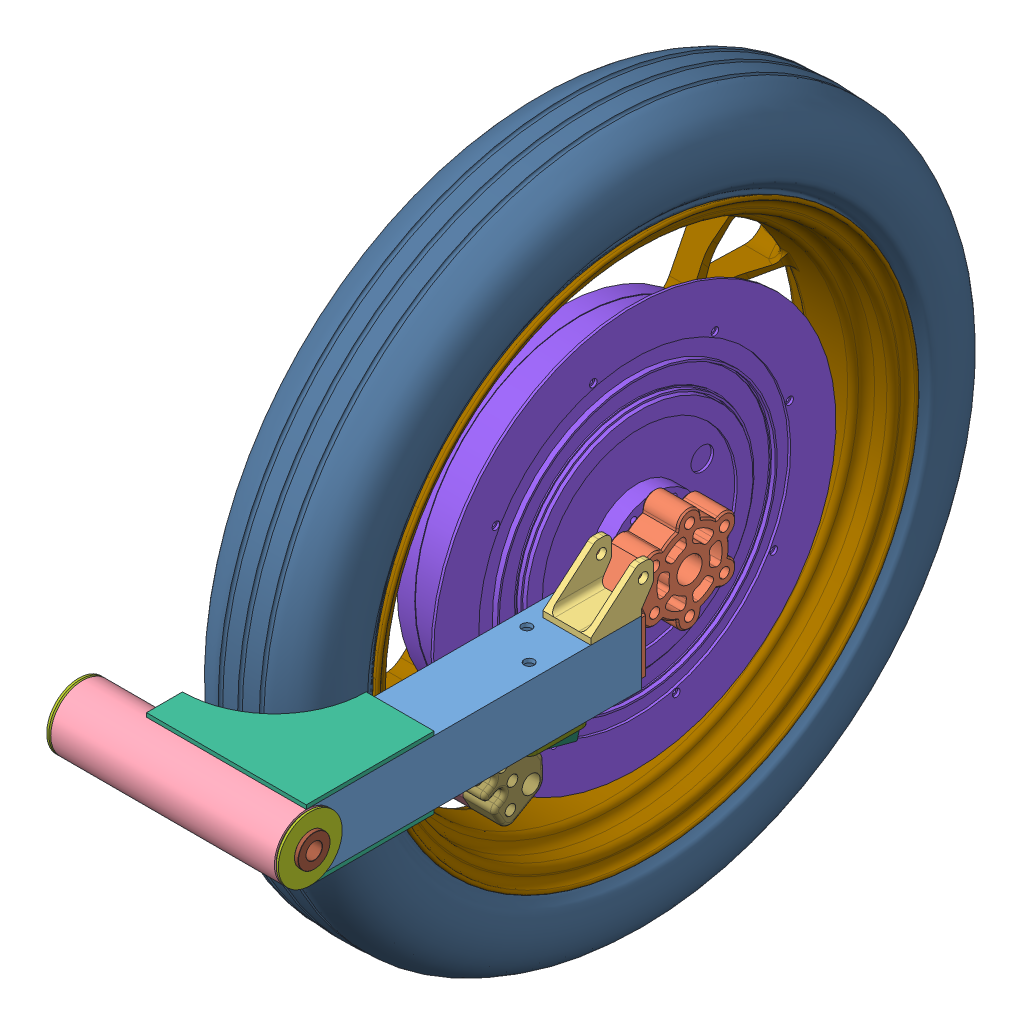
SolidWorks assembly Rear Round Tube Assembly, configuration Default. Lengths in mm.
Overall size (190.5 437.13 595.81).
21 component instances, 16 part files, 42 mates.
Components (placement in the parent):
- Rear Torque Tube-1: Rear Torque Tube [Default] at (-90.1765 35.8174 163.51) size (50.8 50.8 260.35)
- Rear Cap insert-1: Rear Cap insert [Default] at (-42.5515 83.4424 163.51) x (-1 0 0) z (0 0 1) size (63.5 83.05 151.54)
- Rear Brake Bracket-1: Rear Brake Bracket [Default] at (-58.4265 91.3799 178.985) x (1 0 0) z (0 0 -1) size (38.1 36.51 50)
- Rear Round Tube-1: Rear Round Tube [Default] at (-217.1515 61.2174 430.21) x (1 0 0) z (0 -0.469163 -0.883112) size (177.8 50.8 50.8)
- Half Moon Bracket-1: Half Moon Bracket [Default] at (-166.3765 61.2174 430.21) x (0 0 -1) z (0 -1 0) size (22.4 3.17 50.8)
- Rear Gusset-1: Rear Gusset [Default] at (-67.947 35.8174 204.98) x (-1 0 0) z (0 -1 0) size (127 101.6 3.17)
- Rear Gusset-2: Rear Gusset [Default] at (-67.947 89.7924 204.98) x (-1 0 0) z (0 -1 0) size (127 101.6 3.17)
- Rear End Cap-1: Rear End Cap [Default] at (-220.3265 61.2174 430.21) x (1 0 0) z (0 0.040114 0.999195) size (15.88 50.8 50.8)
- Rear End Cap-2: Rear End Cap [Default] at (-36.1765 61.2174 430.21) x (-1 0 0) z (0 -0.104999 -0.994472) size (15.88 50.8 50.8)
- Motor Mitsuba M2096 D-III-1: Motor Mitsuba M2096 D-III [Default] at (-165.0515 61.2174 87.31) x (0 0.866025 -0.5) z (0 0.5 0.866025) size (320 108 320)
- rimmachined v13.2-1: rimmachined v13.2 [Default] at (-156.7515 61.2174 87.31) x (-1 0 0) z (0 0.911723 -0.410807) size (93.59 431.57 431.57) (hidden)
- Michelin Tire-1: Michelin Tire [Default] at (-156.7515 61.2174 87.31) x (-1 0 0) z (0 0 1) size (101.13 556.61 556.61) (hidden)
- 6338K423_Oil-Embedded Flanged Sleeve Bearing (1)-1: 6338K423_Oil-Embedded Flanged Sleeve Bearing (1) [6338K423] at (-213.9765 61.2174 430.21) x (0 0 1) z (-1 0 0) size (25.4 25.4 19.05)
- 6338K423_Oil-Embedded Flanged Sleeve Bearing (1)-3: 6338K423_Oil-Embedded Flanged Sleeve Bearing (1) [6338K423] at (-42.5265 61.2174 430.21) x (0 -0.063789 -0.997963) z (1 0 0) size (25.4 25.4 19.05)
- Caliper Assembly.iam-2: Caliper Assembly.iam [Default] at (-112.6015 -15.8951 220.8728) x (0 0.866025 0.5) z (1 0 0) size (113.01 113.01 50.55)
  - Caliper A v2.ipt-1: Caliper A v2.ipt [Default] x (-1 0 0) z (0 0 -1) size (69.85 44.45 25.27)
  - Caliper B v9.ipt-1: Caliper B v9.ipt [Default] at origin size (69.85 44.45 25.27)
  - MCP 554 Pads v5.ipt-1: MCP 554 Pads v5.ipt [Default] at (0.0125 -5.95 -15.4307) x (-1 0 0) z (0 0 -1) size (63.75 26 7.7)
  - MCP 554 Pads v5.ipt-2: MCP 554 Pads v5.ipt [Default] at (-0.0125 -5.95 -3.5) size (63.75 26 7.7)
  - MCP FWB caliper mounting bracket v1.ipt-1: MCP FWB caliper mounting bracket v1.ipt [Default] at (-30.8831 -83.23 3.175) x (-0.707107 0.707107 0) z (0 0 -1) size (58.07 101.75 3.36) (hidden)
- Right Rear Brake Bracket-1: Right Rear Brake Bracket [Default] at (-112.6015 -12.9309 215.7137) x (0 0.866025 0.5) z (1 0 0) size (100.5 50.71 73.23)
Mates (geometry in assembly coordinates):
- Concentric1: concentric aligned: cylinder of Rear Round Tube-1 through (-39.3515 61.2174 430.21) axis (-1 0 0) radius 22.225; cylinder of Rear End Cap-1 through (-204.4515 61.2174 430.21) axis (-1 0 0) radius 22.225
- Coincident1: coincident aligned: circle of Rear Round Tube-1; plane of Rear End Cap-1 through (-217.1515 61.2174 430.21) normal (1 0 0)
- Concentric2: concentric anti-aligned: cylinder of Rear Round Tube-1 through (-39.3515 61.2174 430.21) axis (-1 0 0) radius 22.225; cylinder of Rear End Cap-2 through (-52.0515 61.2174 430.21) axis (1 0 0) radius 22.225
- Coincident2: coincident anti-aligned: circle of Rear Round Tube-1; plane of Rear End Cap-2 through (-39.3515 61.2174 430.21) normal (-1 0 0)
- Concentric3: concentric aligned: cylinder of Rear End Cap-2 through (-52.0515 61.2174 430.21) axis (1 0 0) radius 9.525; cylinder of 6338K423_Oil-Embedded Flanged Sleeve Bearing (1)-3 through (-52.0515 61.2174 430.21) axis (1 0 0) radius 9.5504
- Coincident3: coincident anti-aligned: plane of Rear End Cap-2 through (-36.1765 61.2174 430.21) normal (1 0 0); plane of 6338K423_Oil-Embedded Flanged Sleeve Bearing (1)-3 through (-36.1765 61.2174 430.21) normal (-1 0 0)
- Concentric4: concentric aligned: cylinder of Rear End Cap-1 through (-204.4515 61.2174 430.21) axis (-1 0 0) radius 9.525; cylinder of 6338K423_Oil-Embedded Flanged Sleeve Bearing (1)-1 through (-204.4515 61.2174 430.21) axis (-1 0 0) radius 9.5504
- Coincident4: coincident anti-aligned: plane of Rear End Cap-1 through (-220.3265 61.2174 430.21) normal (-1 0 0); plane of 6338K423_Oil-Embedded Flanged Sleeve Bearing (1)-1 through (-220.3265 61.2174 430.21) normal (1 0 0)
- Concentric5: concentric anti-aligned: cylinder of Rear Torque Tube-1 through (-90.1765 61.2174 430.21) axis (1 0 0) radius 25.4; cylinder of Rear Round Tube-1 through (-39.3515 61.2174 430.21) axis (-1 0 0) radius 25.4
- Concentric12: concentric aligned: circle of Rear Torque Tube-1; circle of Rear End Cap-2
- Concentric6: concentric aligned: cylinder of Rear Round Tube-1 through (-39.3515 61.2174 430.21) axis (-1 0 0) radius 25.4; cylinder of Half Moon Bracket-1 through (-163.2015 61.2174 430.21) axis (-1 0 0) radius 25.4
- Coincident6: coincident anti-aligned: plane of Rear Torque Tube-1 through (-90.1765 86.6174 423.86) normal (0 1 0); plane of Rear Gusset-2 through (-166.3765 86.6174 328.61) normal (0 -1 0)
- Coincident7: coincident aligned: plane of Rear Torque Tube-1 through (-39.3765 35.8174 423.86) normal (1 0 0); plane of Rear Gusset-2 through (-39.3765 86.6174 430.21) normal (1 0 0)
- Coincident8: coincident: point of Half Moon Bracket-1; point of Rear Gusset-2
- Coincident9: coincident anti-aligned: plane of Rear Torque Tube-1 through (-90.1765 35.8174 423.86) normal (0 -1 0); plane of Rear Gusset-1 through (-166.3765 35.8174 328.61) normal (0 1 0)
- Coincident10: coincident anti-aligned: line of Rear Torque Tube-1 through (-39.3765 35.8174 423.86) axis (0 0 -1); line of Rear Gusset-1 through (-39.3765 35.8174 328.61) axis (0 0 1)
- Coincident11: coincident: point of Half Moon Bracket-1; point of Rear Gusset-1
- Coincident12: coincident anti-aligned: plane of Rear Torque Tube-1 through (-87.0015 83.4424 423.86) normal (0 -1 0); plane of Rear Cap insert-1 through (-42.5515 83.4424 201.61) normal (0 1 0)
- Coincident13: coincident anti-aligned: plane of Rear Torque Tube-1 through (-87.0015 38.9924 423.86) normal (1 0 0); plane of Rear Cap insert-1 through (-87.0015 83.4424 201.61) normal (-1 0 0)
- Coincident15: coincident aligned: line of Rear Torque Tube-1 through (-87.0015 83.4424 163.51) axis (0 -1 0); line of Rear Cap insert-1 through (-87.0015 82.1724 163.51) axis (0 -1 0)
- Coincident16: coincident aligned: line of Rear Torque Tube-1 through (-39.3765 86.6174 423.86) axis (0 0 -1); line of Rear Brake Bracket-1 through (-39.3765 86.6174 203.985) axis (0 0 -1)
- Coincident17: coincident anti-aligned: line of Rear Torque Tube-1 through (-39.3765 86.6174 163.51) axis (-1 0 0); line of Rear Brake Bracket-1 through (-77.4765 86.6174 163.51) axis (1 0 0)
- Concentric7: concentric aligned: cylinder of Rear Cap insert-1 through (-29.8515 77.2174 115.0228) axis (-1 0 0) radius 4; cylinder of Motor Mitsuba M2096 D-III-1 through (-110.0515 77.2174 115.0228) axis (-1 0 0) radius 4
- Concentric8: concentric aligned: cylinder of Rear Cap insert-1 through (-29.8515 93.2174 87.31) axis (-1 0 0) radius 4; cylinder of Motor Mitsuba M2096 D-III-1 through (-110.0515 93.2174 87.31) axis (-1 0 0) radius 4
- Coincident18: coincident anti-aligned: plane of Rear Cap insert-1 through (-106.0515 108.8424 163.51) normal (-1 0 0); plane of Motor Mitsuba M2096 D-III-1 through (-106.0515 61.2174 87.31) normal (1 0 0)
- Concentric9: concentric anti-aligned: cylinder of Motor Mitsuba M2096 D-III-1 through (-179.0515 61.2174 87.31) axis (1 0 0) radius 47; cylinder of rimmachined v13.2-1 through (-165.8515 61.2174 87.31) axis (-1 0 0) radius 47.005
- Coincident19: coincident anti-aligned: plane of Motor Mitsuba M2096 D-III-1 through (-179.0515 61.2174 87.31) normal (-1 0 0); plane of rimmachined v13.2-1 through (-179.0515 77.6497 123.7789) normal (1 0 0)
- Concentric10: concentric aligned: cylinder of rimmachined v13.2-1 through (-71.2423 61.2174 87.31) axis (1 0 0) radius 192.7898; cylinder of Michelin Tire-1 through (-54.0286 61.2174 87.31) axis (1 0 0) radius 203
- Coincident20: coincident aligned: plane of rimmachined v13.2-1 through (-156.7515 61.2174 87.31) normal (-1 0 0); plane of Michelin Tire-1 through (-156.7515 61.2174 87.31) normal (-1 0 0)
- Distance3: distance = 0.75 mm anti-aligned: plane of Caliper Assembly.iam-1/MCP 554 Pads v5.ipt-2 through (-120.3015 0.8714 223.6824) normal (-1 0 0); plane of Motor Mitsuba M2096 D-III-1 through (-121.0515 138.7174 221.5439) normal (1 0 0)
- Tangent3: tangent: plane of Caliper Assembly.iam-2/Caliper A v2.ipt-1 through (-112.6015 -18.637 193.6265) normal (0 0.5 -0.866025)
- Perpendicular2: perpendicular: plane of Caliper Assembly.iam-2/Caliper A v2.ipt-1 through (-112.6015 -18.637 193.6265) normal (0 0.5 -0.866025)
- Coincident28: coincident: plane of Caliper Assembly.iam-2 through (-112.6015 -15.8951 220.8728) normal (0 0.866025 0.5)
- InPlace1: in place: plane of ? through (-112.5765 -11.9255 215.7151) normal (1 0 0); plane of ? through (-112.5765 0 0) normal (1 0 0); moOrthogonalPlaneRef_w of ? through (-112.5765 -11.9255 215.7151) normal (1 0 0); plane of ? through (-112.5765 0 0) normal (0 1 0); plane of ? through (-112.5765 -11.9255 215.7151) normal (1 0 0); plane of ? through (-112.5765 0 0) normal (0 0 -1); plane of Caliper Assembly.iam-2/MCP 554 Pads v5.ipt-2 through (-112.6015 -12.9309 215.7137) normal (1 0 0); unknown of ?
- Coincident29: coincident aligned: plane of Caliper Assembly.iam-2/MCP 554 Pads v5.ipt-2; plane of ?
- Coincident30: coincident aligned: moOrthogonalPlaneRef_w of Caliper Assembly.iam-2/MCP 554 Pads v5.ipt-2 through (-112.6015 -12.9309 215.7137) normal (0 -0.5 0.866025); plane of Left Rear Brake Bracket-1 through (-112.5765 -12.9309 215.7137) normal (0 -0.5 0.866025)
- Coincident31: coincident anti-aligned: moOrthogonalPlaneRef_w of Caliper Assembly.iam-2/MCP 554 Pads v5.ipt-2 through (-112.6015 -12.9309 215.7137) normal (0 -0.866025 -0.5); plane of Left Rear Brake Bracket-1 through (-112.5765 -12.9309 215.7137) normal (0 0.866025 0.5)
- Parallel5: parallel aligned: plane of Rear Torque Tube-1 through (-90.1765 86.6174 423.86) normal (0 1 0)
- Coincident29: coincident anti-aligned: plane of Rear Torque Tube-1 through (-90.1765 35.8174 423.86) normal (0 -1 0); plane of Right Rear Brake Bracket-1 through (12.3583 35.8174 252.9458) normal (0 1 0)
- Coincident30: coincident anti-aligned: plane of Caliper Assembly.iam-2/MCP 554 Pads v5.ipt-2 through (-112.6015 -12.9309 215.7137) normal (1 0 0); plane of Right Rear Brake Bracket-1 through (-112.6015 -13.5138 216.7483) normal (-1 0 0)
- Concentric11: concentric aligned: circle of Caliper Assembly.iam-2/Caliper A v2.ipt-1; cylinder of Right Rear Brake Bracket-1 through (-109.4265 -33.3423 203.4673) axis (-1 0 0) radius 5.2705
- Coincident31: coincident anti-aligned: plane of Rear Round Tube-1 through (-39.3515 61.2174 430.21) normal (1 0 0); plane of Rear End Cap-2 through (-39.3515 61.2174 430.21) normal (-1 0 0)
